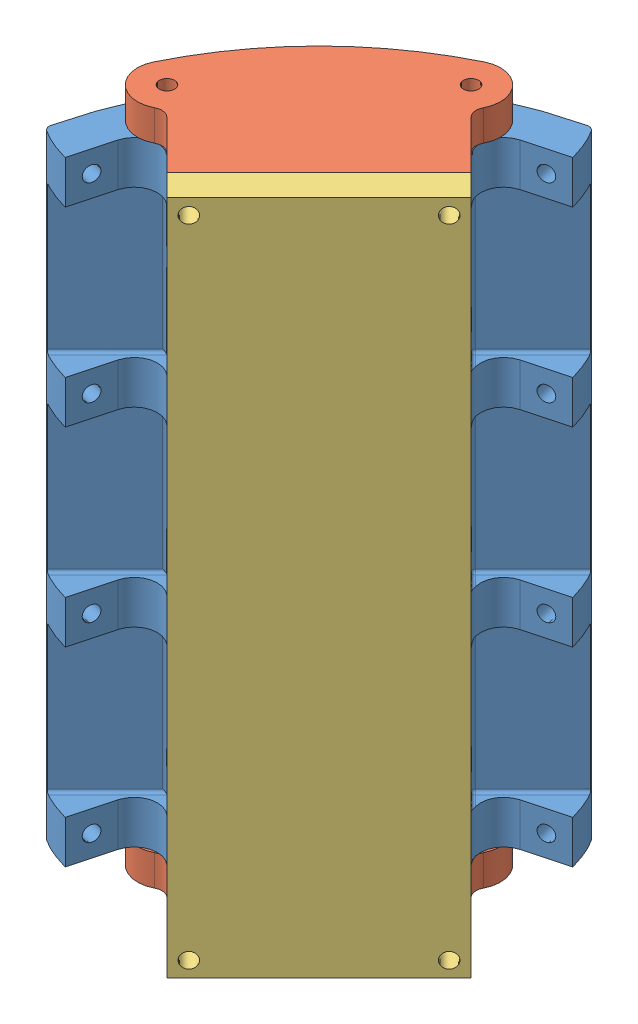
SolidWorks assembly 10008-R06_LOWER_AVIONICS_BAY, configuration Default. Lengths in mm.
Overall size (125.47 279.4 125.47).
4 component instances, 3 part files, 7 mates.
Components (placement in the parent):
- 14026-R05_LOWER_AVIONICS_MIDSECTION-1: 14026-R05_LOWER_AVIONICS_MIDSECTION [Default] at (40.0242 -108.7505 97.193) size (119.48 254 119.48)
- 14029-R04_LOWER_AVIONICS_END-1: 14029-R04_LOWER_AVIONICS_END [Default] at (18.7495 145.2495 -0.4118) x (0.999999 0 -0.001042) z (0.001042 0 0.999999) size (106.49 12.7 106.42)
- 14029-R04_LOWER_AVIONICS_END-2: 14029-R04_LOWER_AVIONICS_END [Default] at (-57.5806 -108.7505 75.9182) x (-0.001042 0 0.999999) z (0.999999 0 0.001042) size (106.49 12.7 106.42)
- 14030-R03_LOWER_AVIONICS_LID-1: 14030-R03_LOWER_AVIONICS_LID [Default] at (-20.1935 18.2495 36.9753) x (0.707107 0 -0.707107) z (0 -1 0) size (88.83 12.7 279.4)
Mates (geometry in assembly coordinates):
- Coincident1: coincident: circle of 14026-R05_LOWER_AVIONICS_MIDSECTION-1; circle of 14029-R04_LOWER_AVIONICS_END-1
- Coincident2: coincident: circle of 14026-R05_LOWER_AVIONICS_MIDSECTION-1; circle of 14029-R04_LOWER_AVIONICS_END-1
- Coincident4: coincident: circle of 14026-R05_LOWER_AVIONICS_MIDSECTION-1; circle of 14029-R04_LOWER_AVIONICS_END-2
- Coincident5: coincident: circle of 14026-R05_LOWER_AVIONICS_MIDSECTION-1; circle of 14029-R04_LOWER_AVIONICS_END-2
- Coincident17: coincident: plane of 14029-R04_LOWER_AVIONICS_END-1 through (11.2117 157.9495 5.5701) normal (0.707107 0 0.707107); plane of 14030-R03_LOWER_AVIONICS_LID-1 through (-20.1935 18.2495 36.9753) normal (-0.707107 0 -0.707107)
- Concentric1: concentric: cylinder of 14029-R04_LOWER_AVIONICS_END-1 through (-2.2586 151.5995 1.08) axis (0.707107 0 0.707107) radius 3.175; cylinder of 14030-R03_LOWER_AVIONICS_LID-1 through (6.7216 151.5995 10.0602) axis (0.707107 0 0.707107) radius 3.175
- Concentric2: concentric: cylinder of 14029-R04_LOWER_AVIONICS_END-2 through (-56.0888 -115.1005 54.9101) axis (0.707107 0 0.707107) radius 3.175; cylinder of 14030-R03_LOWER_AVIONICS_LID-1 through (-47.1085 -115.1005 63.8904) axis (0.707107 0 0.707107) radius 3.175
